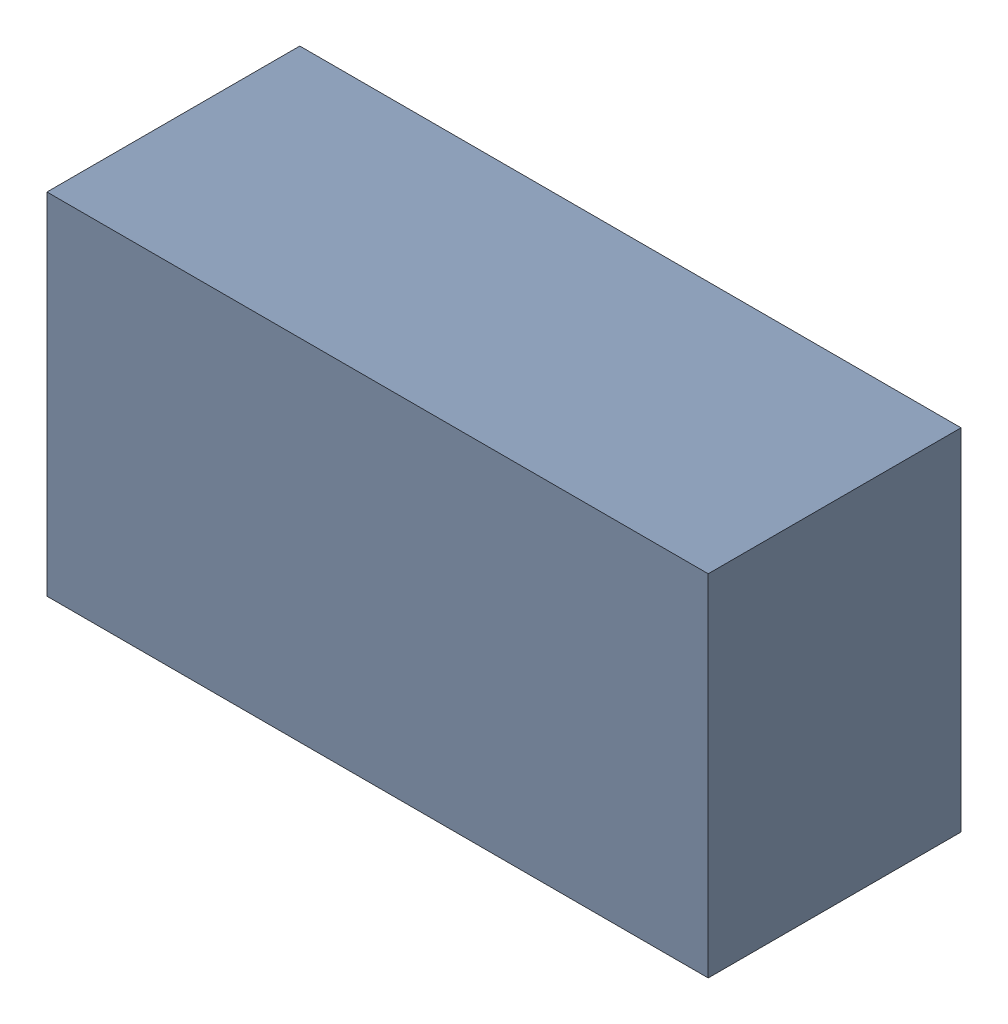
SolidWorks assembly C3, configuration Default. Lengths in mm.
Overall size (3.4 1.8 1.3).
2 component instances, 1 part files, 0 mates.
Components (placement in the parent):
- 580487568-1: 580487568 [Default] at (215.138 111.887 0) size (3.4 1.8 1.3)
  - Extruded_5-1: Extruded_5 [Default] at origin size (3.4 1.8 1.3)
